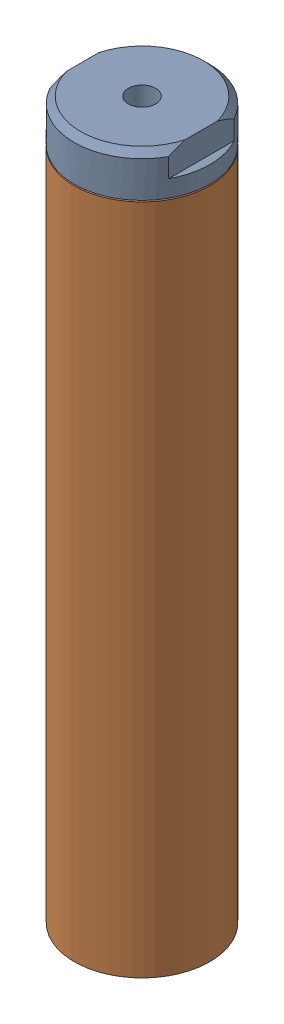
SolidWorks assembly BLB-10, configuration Default. Lengths in mm.
Overall size (25.4 134.16 25.4).
4 component instances, 3 part files, 0 mates.
Components (placement in the parent):
- BLB-ASM10-1: BLB-ASM10 [Default] at origin size (25.4 134.16 25.4)
  - BS-18-33R-1: BS-18-33R [Default] at origin size (25.4 12.7 25.4)
  - BT-33R-SM-1: BT-33R-SM [Default] at (0 -121.4628 0) size (25.4 126.21 25.4)
  - RNG18COP-1: RNG18COP [Default] at (0 -0.5842 0) size (24.13 1.07 24.12)
